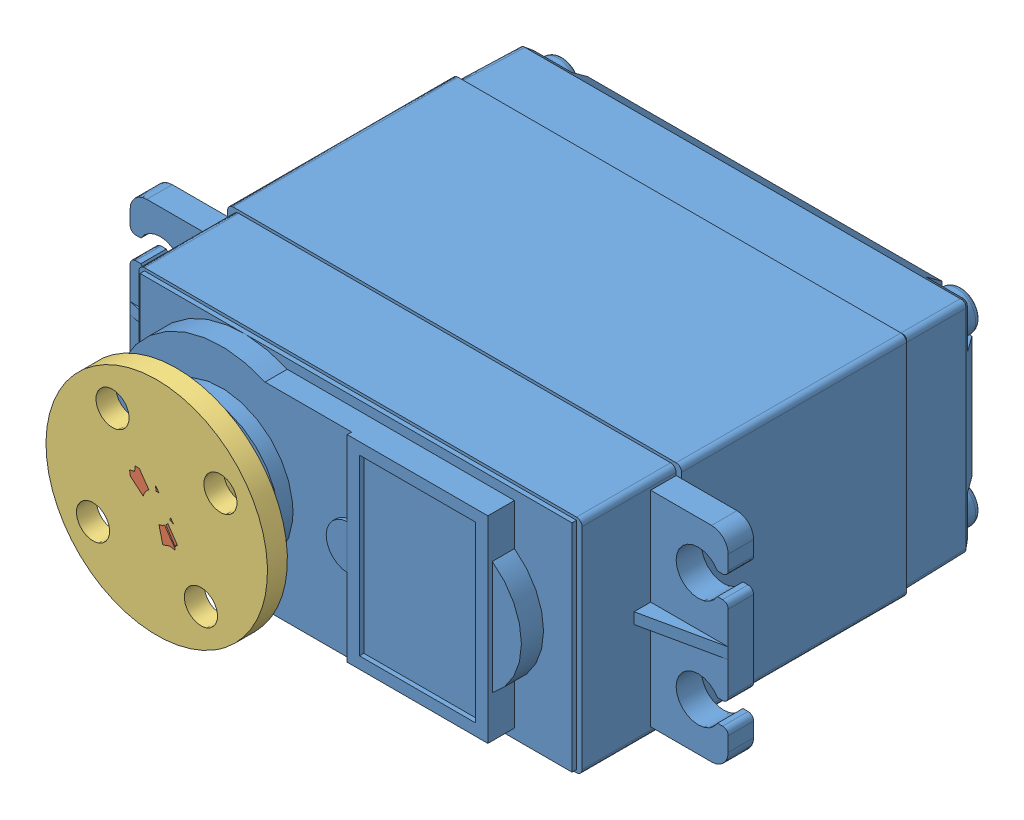
SolidWorks assembly 3423Model_Spider_OfDinh_Motor_MG966R_ASM, configuration Default. Lengths in mm.
Overall size (54.5 27.83 44.7).
3 component instances, 3 part files, 4 mates.
Components (placement in the parent):
- 3423Model_Spider_OfDinh_Motor_ServoMG966R-1: 3423Model_Spider_OfDinh_Motor_ServoMG966R [По умолчанию] at (25.4655 37.2326 19.0996) size (54.5 20.5 40.7)
- 3423Model_Spider_OfDinh_Motor_Motor_Shaft-1: 3423Model_Spider_OfDinh_Motor_Motor_Shaft [Default] at (15.2655 37.2326 51.2996) x (0.110151 0.993915 0) z (0.993915 -0.110151 0) size (6 9 6)
- 3423Model_Spider_OfDinh_Motor_ArmCricle-2: 3423Model_Spider_OfDinh_Motor_ArmCricle [Default] at (15.2655 37.2326 56.2996) x (-0.821588 -0.570082 0) z (0.570082 -0.821588 0) size (20 4.5 20)
Mates (geometry in assembly coordinates):
- Концентричный1: concentric aligned: cylinder of 221023_Model_DoAn_Group_2_Motor_ServoMG966R-1 through (15.2655 37.2326 47.2996) axis (0 0 1) radius 3; cylinder of 221023_Model_DoAn_Group_2_Motor_Shaft-1 through (15.2655 37.2326 47.2996) axis (0 0 1) radius 3
- Совпадение1: coincident anti-aligned: plane of 221023_Model_DoAn_Group_2_Motor_ServoMG966R-1 through (15.2655 37.2326 47.2996) normal (0 0 1); plane of 221023_Model_DoAn_Group_2_Motor_Shaft-1 through (15.2655 37.2326 47.2996) normal (0 0 -1)
- Concentric3: concentric aligned: cylinder of 221023_Model_DoAn_Group_2_Motor_Shaft-1 through (15.2655 37.2326 49.2996) axis (0 0 1) radius 1.25; cylinder of 3423Model_Spider_OfDinh_Motor_ArmCricle-2 through (15.2655 37.2326 54.4996) axis (0 0 1) radius 2.5
- Coincident3: coincident aligned: plane of 221023_Model_DoAn_Group_2_Motor_Shaft-1 through (15.2655 37.2326 56.2996) normal (0 0 1); plane of 3423Model_Spider_OfDinh_Motor_ArmCricle-2 through (15.2655 37.2326 56.2996) normal (0 0 1)
